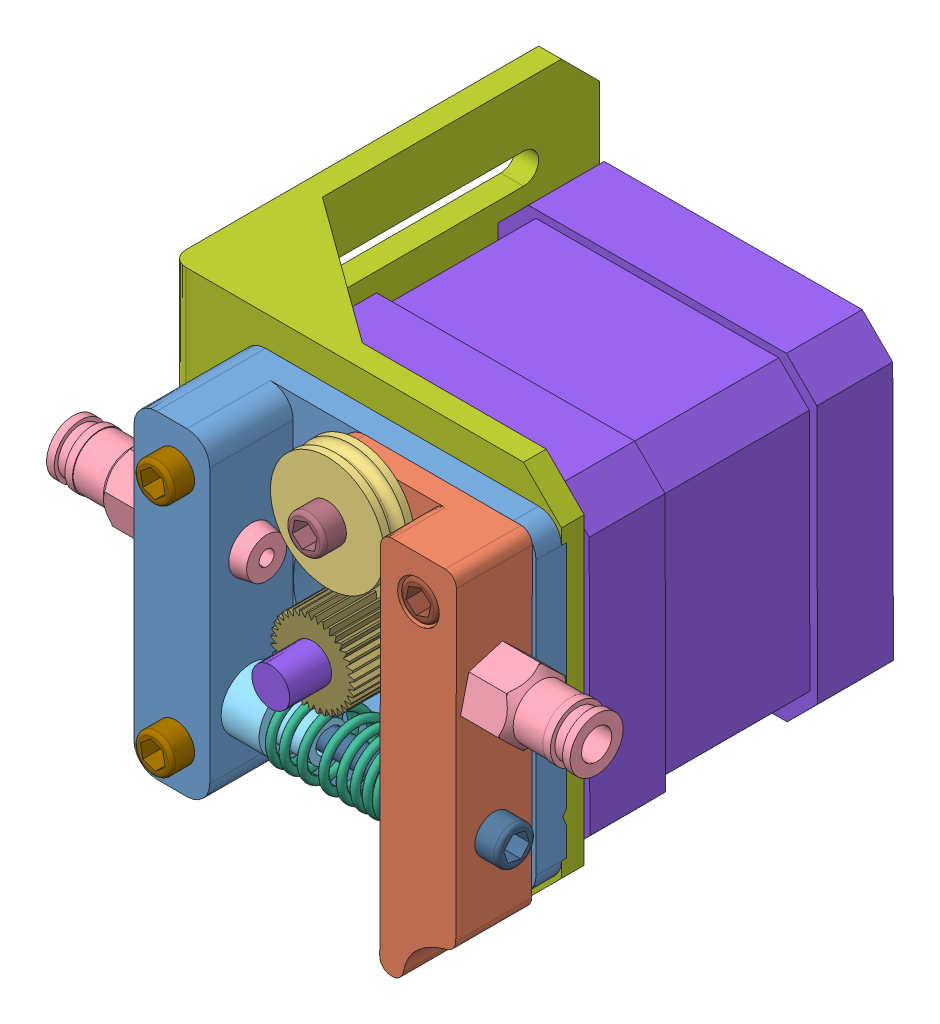
SolidWorks assembly Bowden Assembly, configuration Default. Lengths in mm.
Overall size (68.49 54.01 70.85).
16 component instances, 14 part files, 32 mates.
Components (placement in the parent):
- Main Block-1: Main Block [Default] at (16.5906 16.7583 27.7621) size (42 42 15)
- Arm-1: Arm [Default] at (32.0447 12.7584 31.7621) x (0.999997 -0.002353 0) z (0 0 1) size (25 50 10)
- Feed Bearing-1: Feed Bearing [Default] at (17.0906 32.2936 34.7621) size (15 15 4)
- PTFE 4mm Fitting-1: PTFE 4mm Fitting [Default] at (7.5906 22.7583 37.2621) x (0 0 1) z (-1 0 0) size (9.52 9.62 25.5)
- PTFE 4mm Fitting-2: PTFE 4mm Fitting [Default] at (25.0683 22.7748 36.7621) x (0 0 -1) z (0.999997 -0.002353 0) size (9.52 9.62 25.5)
- Adjust Mount-1: Adjust Mount [Default] at (5.5906 5.7583 37.2621) x (0 0 -1) z (1 0 0) size (8 8 10)
- Compression Spring-1: Compression Spring [Default] at (26.6918 6.1319 36.8921) x (-0.03687 0.954593 -0.295622) z (-0.999309 -0.03662 0.006384) size (9 9 16.75)
- Bowden LBracket-1: Bowden LBracket [Default] at (-13.9094 16.7583 1.6668) x (0 0 -1) z (1 0 0) size (53.5 50 51.5)
- Bowben Nema 17-1: Bowben Nema 17 [Default] at (16.6316 16.7994 -15.2379) x (0.999996 0.002653 0) z (0 0 1) size (42 42 61)
- Hex M3x22-5: Hex M3x22 [Default] at (1.0906 1.2583 45.7621) x (0.230478 -0.973077 0) z (0 0 -1) size (5 5 25)
- Hex M3x22-7: Hex M3x22 [Default] at (1.0906 32.2583 45.7621) x (0.230478 -0.973077 0) z (0 0 -1) size (5 5 25)
- Hex M3x25-1: Hex M3x25 [Default] at (40.0282 5.7396 36.7621) x (0.002187 0.92966 0.368411) z (-0.999997 0.002353 0) size (5 5 28)
- Hex M3x20-3: Hex M3x20 [Default] at (32.0906 32.2583 41.7621) x (-0.923728 -0.383049 0) z (0 0 -1) size (5 5 23)
- Toothed Filament Feed-1: Toothed Filament Feed [Default] at (16.6316 16.7994 40.2533) x (-0.928407 -0.371565 0) z (0 0 -1) size (10.98 10.98 11)
- Hex M3x6-1: Hex M3x6 [Default] at (17.0906 32.2936 41.7621) x (-0.923728 -0.383049 0) z (0 0 -1) size (5 5 9)
- Hex M3x15-1: Hex M3x15 [Default] at (-7.4094 5.7583 37.2621) x (0 -0.924225 -0.381849) z (1 0 0) size (5 5 18)
Mates (geometry in assembly coordinates):
- Concentric1: concentric: cylinder of Main Block-1 through (32.0906 32.2583 21.7621) axis (0 0 1) radius 1.75; cylinder of Arm-1 through (32.0906 32.2583 31.7621) axis (0 0 1) radius 1.75
- Coincident1: coincident: plane of Main Block-1 through (16.5906 16.7583 31.7621) normal (0 0 1); plane of Arm-1 through (32.0447 12.7584 31.7621) normal (0 0 -1)
- Concentric2: concentric: cylinder of Arm-1 through (17.0906 32.2936 19.7621) axis (0 0 1) radius 1.35; cylinder of Feed Bearing-1 through (17.0906 32.2936 33.7621) axis (0 0 1) radius 1.5
- Coincident2: coincident: plane of Arm-1 through (12.1036 37.8054 34.7621) normal (0 0 1); plane of Feed Bearing-1 through (17.0906 32.2936 34.7621) normal (0 0 -1)
- Concentric3: concentric: cylinder of Main Block-1 through (16.5906 22.7583 37.2621) axis (-1 0 0) radius 3; cylinder of PTFE 4mm Fitting-1 through (-4.4094 22.7583 37.2621) axis (1 0 0) radius 3
- Coincident3: coincident: plane of Main Block-1 through (-4.4094 37.7583 31.7621) normal (-1 0 0); plane of PTFE 4mm Fitting-1 through (-4.4094 22.7583 37.2621) normal (1 0 0)
- Concentric4: concentric: cylinder of Arm-1 through (24.0683 22.7772 36.7621) axis (0.999997 -0.002353 0) radius 3; cylinder of PTFE 4mm Fitting-2 through (37.0682 22.7466 36.7621) axis (-0.999997 0.002353 0) radius 3
- Coincident4: coincident: plane of Arm-1 through (37.1035 37.7465 41.7621) normal (0.999997 -0.002353 0); plane of PTFE 4mm Fitting-2 through (37.0682 22.7466 36.7621) normal (-0.999997 0.002353 0)
- Coincident5: coincident: plane of Main Block-1 through (5.5906 37.7583 42.7621) normal (1 0 0); plane of Adjust Mount-1 through (5.5906 5.7583 37.2621) normal (-1 0 0)
- Coincident6: coincident: plane of Main Block-1 through (5.5906 37.7583 42.7621) normal (1 0 0); plane of Adjust Mount-1 through (5.5906 5.7583 37.2621) normal (-1 0 0)
- Concentric5: concentric: cylinder of Main Block-1 through (16.5906 5.7583 37.2621) axis (-1 0 0) radius 1.5; cylinder of Adjust Mount-1 through (15.5906 5.7583 37.2621) axis (-1 0 0) radius 1.5
- Coincident9: coincident: plane of Main Block-1 through (16.5906 16.7583 42.7621) normal (0 0 1); plane of ? through (1.0906 32.2583 42.7621) normal (0 0 -1)
- Concentric10: concentric: cylinder of Main Block-1 through (1.0906 32.2583 21.7621) axis (0 0 1) radius 1.75; cylinder of ? through (1.0906 32.2583 20.7621) axis (0 0 1) radius 1.5
- Coincident10: coincident: plane of Main Block-1 through (16.5906 16.7583 42.7621) normal (0 0 1); plane of Hex M3x22-5 through (1.0906 1.2583 42.7621) normal (0 0 -1)
- Concentric11: concentric: cylinder of Main Block-1 through (1.0906 1.2583 21.7621) axis (0 0 1) radius 1.75; cylinder of Hex M3x22-5 through (1.0906 1.2583 20.7621) axis (0 0 1) radius 1.5
- Concentric12: concentric: cylinder of Main Block-1 through (1.0906 32.2583 21.7621) axis (0 0 1) radius 1.75; cylinder of Hex M3x22-7 through (1.0906 32.2583 20.7621) axis (0 0 1) radius 1.5
- Coincident11: coincident: plane of Main Block-1 through (16.5906 16.7583 42.7621) normal (0 0 1); plane of Hex M3x22-7 through (1.0906 32.2583 42.7621) normal (0 0 -1)
- Coincident12: coincident: plane of Arm-1 through (32.0906 32.2583 38.7621) normal (0 0 1); plane of Hex M3x20-3 through (32.0906 32.2583 38.7621) normal (0 0 -1)
- Concentric13: concentric: cylinder of Arm-1 through (32.0906 32.2583 31.7621) axis (0 0 1) radius 1.75; cylinder of Hex M3x20-3 through (32.0906 32.2583 13.7621) axis (0 0 1) radius 1.5
- Concentric14: concentric: cylinder of Arm-1 through (22.0223 5.7842 36.7621) axis (0.999997 -0.002579 0) radius 1.5; cylinder of ? through (17.0223 5.7971 36.7621) axis (0.999997 -0.002579 0) radius 1.5
- Coincident13: coincident: plane of Arm-1; plane of ? through (37.0222 5.7455 36.7621) normal (-0.999997 0.002579 0)
- Concentric15: concentric: cylinder of Arm-1 through (22.0283 5.7819 36.7621) axis (0.999997 -0.002353 0) radius 1.5; cylinder of Hex M3x25-1 through (12.0283 5.8054 36.7621) axis (0.999997 -0.002353 0) radius 1.5
- Coincident14: coincident: plane of Arm-1 through (37.1035 37.7465 41.7621) normal (0.999997 -0.002353 0); plane of Hex M3x25-1 through (37.0282 5.7466 36.7621) normal (-0.999997 0.002353 0)
- Coincident15: coincident: plane of Arm-1 through (32.0906 32.2583 38.7621) normal (0 0 1); plane of Hex M3x20-3 through (32.0906 32.2583 38.7621) normal (0 0 -1)
- Concentric16: concentric: cylinder of Arm-1 through (32.0906 32.2583 31.7621) axis (0 0 1) radius 1.75; cylinder of Hex M3x20-3 through (32.0906 32.2583 18.7621) axis (0 0 1) radius 1.5
- Concentric17: concentric: cylinder of Bowben Nema 17-1 through (16.6316 16.7994 45.7621) axis (0 0 -1) radius 2.5; cylinder of Toothed Filament Feed-1 through (16.6316 16.7994 41.2533) axis (0 0 -1) radius 2.5
- Concentric18: concentric: cylinder of Feed Bearing-1 through (17.0906 32.2936 33.7621) axis (0 0 1) radius 1.5; cylinder of Hex M3x6-1 through (17.0906 32.2936 32.7621) axis (0 0 1) radius 1.5
- Coincident16: coincident: plane of Feed Bearing-1 through (17.0906 32.2936 38.7621) normal (0 0 1); plane of Hex M3x6-1 through (17.0906 32.2936 38.7621) normal (0 0 -1)
- Concentric19: concentric: cylinder of Main Block-1 through (16.5906 5.7583 37.2621) axis (-1 0 0) radius 1.5; cylinder of Hex M3x15-1 through (10.5906 5.7583 37.2621) axis (-1 0 0) radius 1.5
- Coincident17: coincident: plane of Main Block-1 through (-4.4094 37.7583 31.7621) normal (-1 0 0); plane of Hex M3x15-1 through (-4.4094 5.7583 37.2621) normal (1 0 0)
- Concentric20: concentric aligned: cylinder of Bowden LBracket-1 through (32.0906 32.2583 18.4168) axis (0 0 1) radius 1.75; cylinder of Hex M3x20-3 through (32.0906 32.2583 18.7621) axis (0 0 1) radius 1.5
- Concentric21: concentric aligned: cylinder of Bowden LBracket-1 through (1.0906 1.2583 18.4168) axis (0 0 1) radius 1.75; cylinder of Hex M3x22-5 through (1.0906 1.2583 20.7621) axis (0 0 1) radius 1.5
